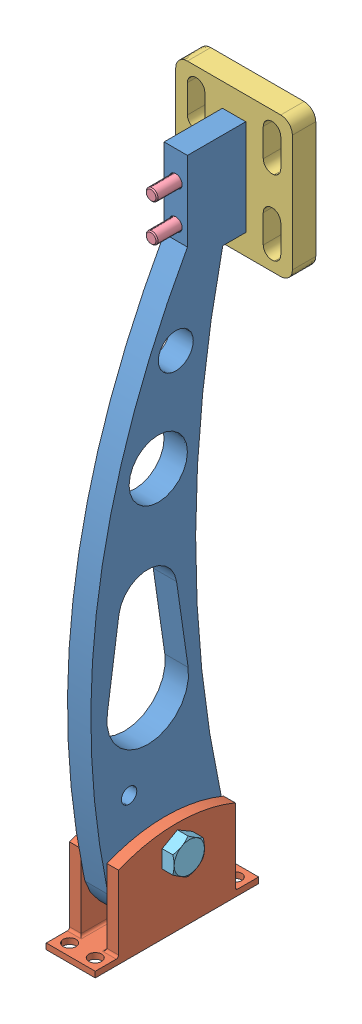
SolidWorks assembly Brake pedal assembly, configuration Default. Lengths in mm.
Overall size (50 290 82.09).
6 component instances, 5 part files, 11 mates.
Components (placement in the parent):
- Pedal support-1: Pedal support [Default] at (-18.1752 -126.5332 15.7631) size (10 275 71.45)
- Base Pedal Interface-1: Base Pedal Interface [Default] at (-23.9287 -156.5332 -9.2369) size (21 40 70)
- Brake pedal only-1: Brake pedal only [Default] at (11.8087 73.4668 -19.2369) x (-1 0 0) z (0 0 -1) size (50 60 10)
- din_en_iso2010_m5x45_4_8-1: din_en_iso2010_m5x45_4_8 [Default] at (-13.1913 95.4668 -29.8984) size (9.22 9.3 46.18)
- din_en_iso2010_m5x45_4_8-2: din_en_iso2010_m5x45_4_8 [Default] at (-13.1913 111.4668 -29.8984) size (9.22 9.3 46.18)
- din_en_24017_m8x35-1: din_en_24017_m8x35 [Default] at (-2.6752 -126.5332 15.7631) x (0 0.00881 0.999961) z (-1 0 0) size (13 15.01 40.3)
Mates (geometry in assembly coordinates):
- Concentric1: concentric aligned: circle of Pedal support-1; circle of Base Pedal Interface-1
- Distance3: distance = 0.5 mm anti-aligned: plane of Base Pedal Interface-1 through (-7.6752 -106.5332 40.7631) normal (-1 0 0); plane of Pedal support-1 through (-8.1752 -19.2942 43.7338) normal (1 0 0)
- Concentric2: concentric anti-aligned: circle of Pedal support-1; circle of Brake pedal only-1
- Concentric3: concentric anti-aligned: circle of Pedal support-1; circle of Brake pedal only-1
- Coincident8: coincident anti-aligned: plane of Pedal support-1 through (-8.1752 82.3648 -19.2369) normal (0 0 -1); plane of Brake pedal only-1 through (11.8087 73.4668 -19.2369) normal (0 0 1)
- Concentric4: concentric aligned: cylinder of Pedal support-1 through (-13.1913 111.4668 -19.2369) axis (0 0 -1) radius 2.75; cylinder of din_en_iso2010_m5x45_4_8-2 through (-13.1913 111.4668 -29.8984) axis (0 0 -1) radius 2.5
- Coincident9: coincident: cone of Brake pedal only-1 through (-13.1913 111.4668 -29.2369) axis (0 0 1); circle of din_en_iso2010_m5x45_4_8-2
- Concentric6: concentric aligned: cylinder of Pedal support-1 through (-13.1913 95.4668 -19.2369) axis (0 0 -1) radius 2.75; cylinder of din_en_iso2010_m5x45_4_8-1 through (-13.1913 95.4668 -29.8984) axis (0 0 -1) radius 2.5
- Coincident10: coincident: cone of Brake pedal only-1 through (-13.1913 95.4668 -29.2369) axis (0 0 1); circle of din_en_iso2010_m5x45_4_8-1
- Concentric7: concentric aligned: cylinder of Pedal support-1 through (-8.1752 -126.5332 15.7631) axis (1 0 0) radius 4.5; cylinder of din_en_24017_m8x35-1 through (-2.0252 -126.5332 15.7631) axis (1 0 0) radius 4
- Coincident11: coincident anti-aligned: plane of Base Pedal Interface-1 through (-2.6752 -106.5332 40.7631) normal (1 0 0); plane of din_en_24017_m8x35-1 through (-2.6752 -122.1333 15.7243) normal (-1 0 0)
